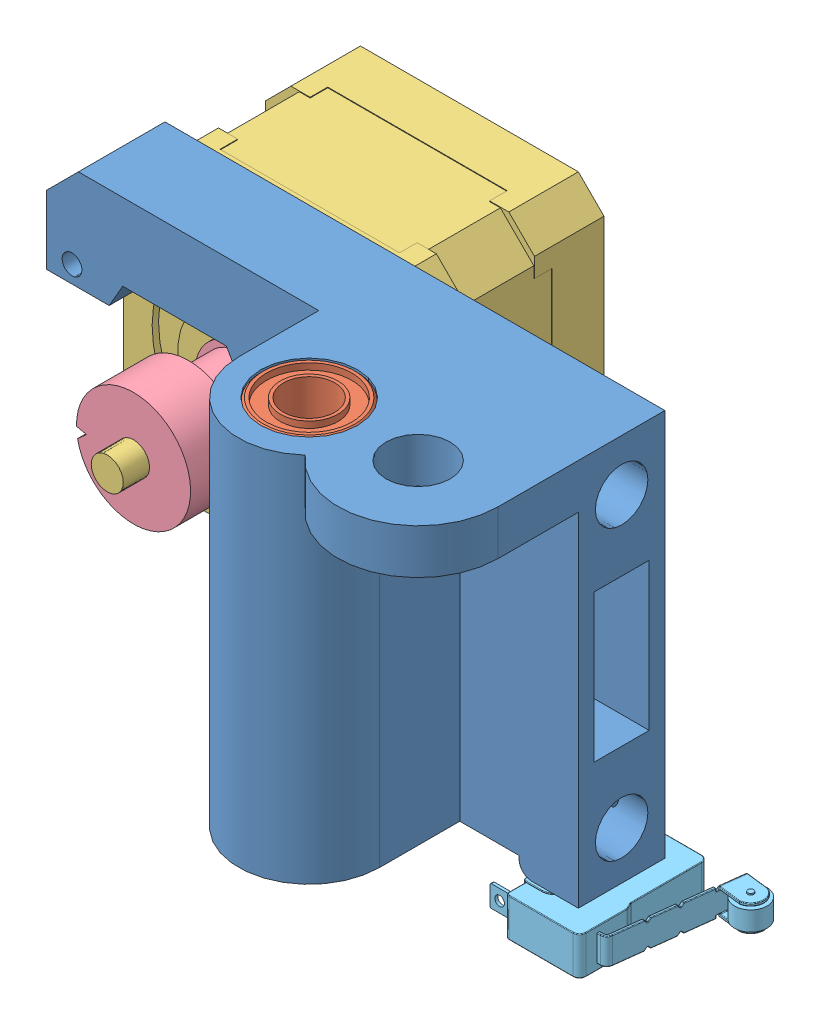
SolidWorks assembly SE-X-motor-with-NEMA17, configuration Predeterminado. Lengths in mm.
Overall size (89.39 66.75 71.5).
6 component instances, 5 part files, 12 mates.
Components (placement in the parent):
- X-Motor-1: X-Motor [Predeterminado] at (7.2089 20.4592 92) size (83 60.5 38.5)
- LM8UU-1: LM8UU [Default] at (7.2089 15.4592 92) x (0 1 0) z (0 0 1) size (24 15 15)
- LM8UU-2: LM8UU [Default] at (7.2089 -18.5408 92) x (0 1 0) z (0 0 1) size (24 15 15)
- NEMA17-1: NEMA17 [Default] at (-26.7911 -1.0408 49.5) x (0 0 1) z (-1 0 0) size (56.5 42 42)
- GT2Pulley-1: GT2Pulley [Predeterminado] at (-26.7911 -1.0408 85.4) x (-0.542329 0.840166 0) z (-0.840166 -0.542329 0) size (17.8 17.6 17.8)
- Endstop-1: Endstop [Valor predeterminado] at (40.4589 -36.1658 72.8) x (0 0 1) z (0 1 0) size (22.72 24.55 6.25)
Mates (geometry in assembly coordinates):
- Concéntrica1: concentric aligned: cylinder of X-Motor-1 through (7.2089 27.4592 92) axis (0 -1 0) radius 7.55; cylinder of LM8UU-1 through (7.2089 -30.2303 92) axis (0 -1 0) radius 7.5
- Coincidente1: coincident aligned: plane of X-Motor-1 through (7.2089 27.4592 92) normal (0 1 0); plane of LM8UU-1 through (7.2089 27.4592 92) normal (0 1 0)
- Concéntrica2: concentric aligned: cylinder of X-Motor-1 through (7.2089 27.4592 92) axis (0 -1 0) radius 7.55; cylinder of LM8UU-2 through (7.2089 -64.2303 92) axis (0 -1 0) radius 7.5
- Coincidente2: coincident aligned: plane of X-Motor-1 through (7.2089 -30.5408 92) normal (0 -1 0); circle of LM8UU-2
- Concéntrica3: concentric aligned: cylinder of X-Motor-1 through (-42.2911 14.4592 66) axis (0 0 1) radius 1.55; cylinder of NEMA17-1 through (-42.2911 14.4592 66) axis (0 0 1) radius 1.275
- Concéntrica4: concentric aligned: cylinder of X-Motor-1 through (-11.2911 14.4592 66) axis (0 0 1) radius 1.55; cylinder of NEMA17-1 through (-11.2911 14.4592 66) axis (0 0 1) radius 1.275
- Concéntrica5: concentric aligned: cylinder of X-Motor-1 through (-11.2911 -16.5408 66) axis (0 0 1) radius 1.55; cylinder of NEMA17-1 through (-11.2911 -16.5408 66) axis (0 0 1) radius 1.275
- Coincidente5: coincident anti-aligned: plane of X-Motor-1 through (36.7089 27.4592 66) normal (0 0 -1); plane of NEMA17-1 through (-26.7911 -1.0408 66) normal (0 0 1)
- Concéntrica6: concentric aligned: cylinder of NEMA17-1 through (-26.7911 -1.0408 63.775) axis (0 0 1) radius 2.5; cylinder of GT2Pulley-1 through (-26.7911 -1.0408 76.8) axis (0 0 1) radius 2.5
- Distancia1: distance = 0.3 mm anti-aligned: plane of NEMA17-1 through (-26.7911 -1.0408 67.5) normal (0 0 1); plane of GT2Pulley-1 through (-26.7911 -1.0408 67.8) normal (0 0 -1)
- Concéntrica7: concentric anti-aligned: cylinder of X-Motor-1 through (31.4589 -29.0408 78) axis (0 -1 0) radius 1; cylinder of Endstop-1 through (31.4589 -39.2908 78) axis (0 1 0) radius 1.475
- Coincidente6: coincident anti-aligned: plane of X-Motor-1 through (7.2089 -33.0408 92) normal (0 -1 0); plane of Endstop-1 through (31.4589 -33.0408 67.6) normal (0 1 0)
